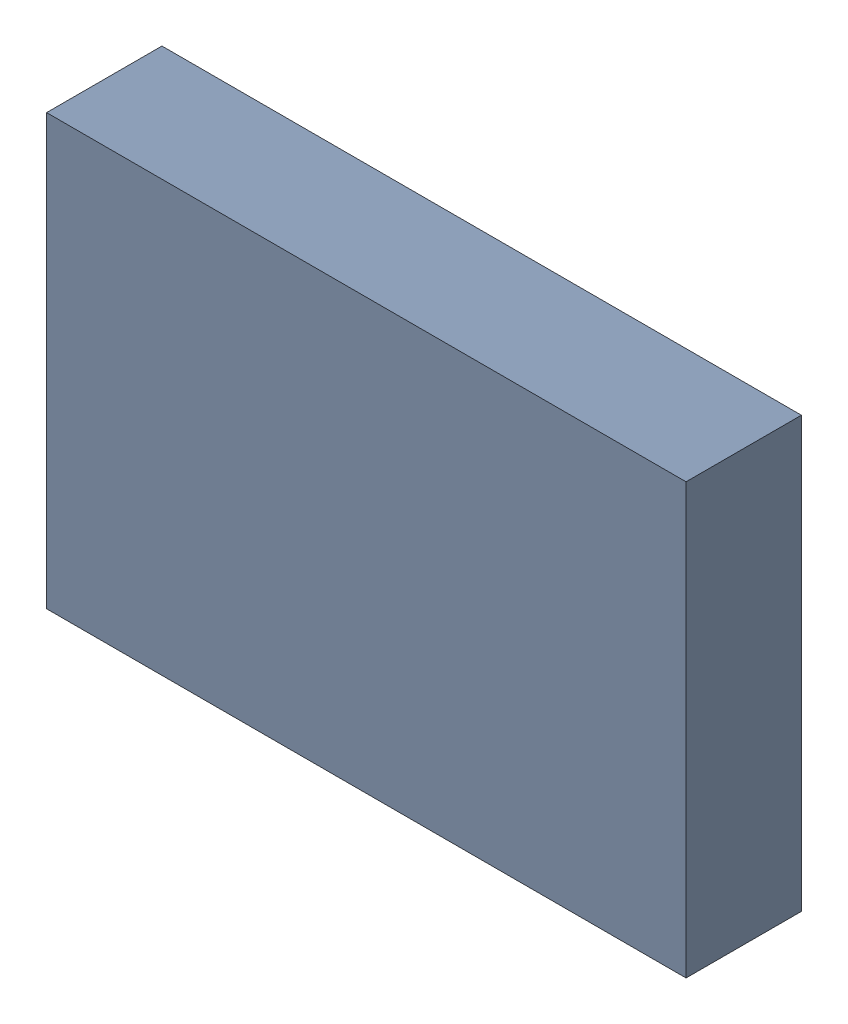
SolidWorks assembly U202PCB, configuration Default. Lengths in mm.
Overall size (3.05 2.05 0.55).
2 component instances, 1 part files, 0 mates.
Components (placement in the parent):
- 846486416-1: 846486416 [Default] at (91.5 122.8 0) size (3.05 2.05 0.55)
  - Extruded_24-1: Extruded_24 [Default] at origin size (3.05 2.05 0.55)
